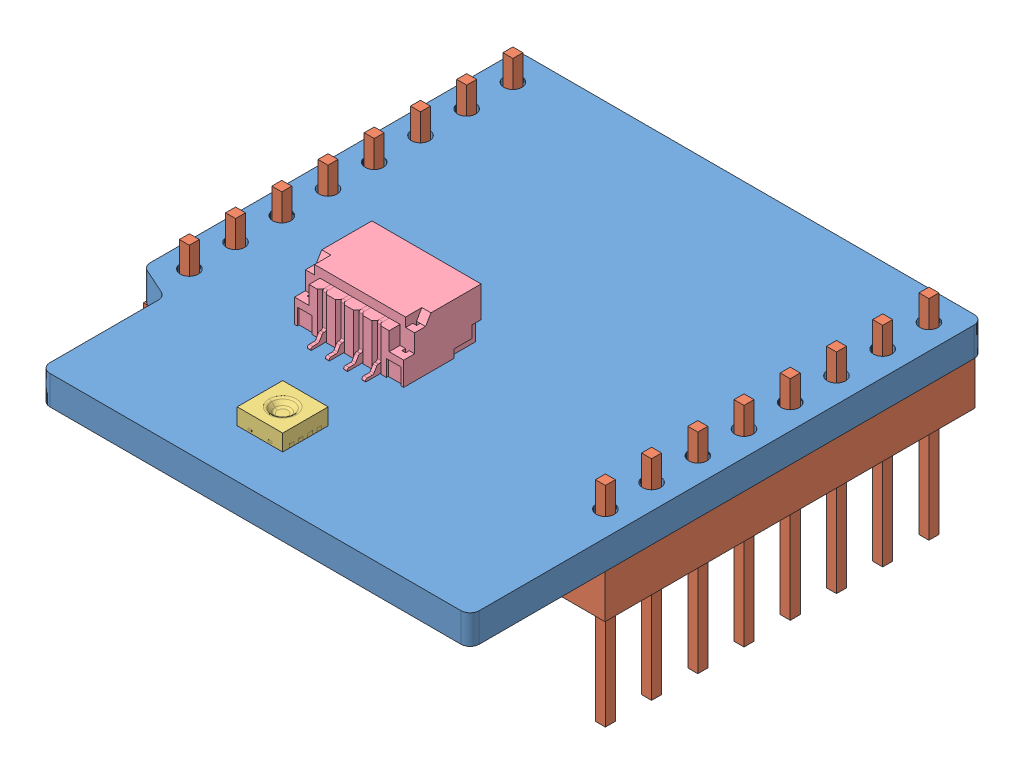
SolidWorks assembly LOLIN SHT30 shield v2.1.0, configuration Default. Lengths in mm.
Overall size (25.6 13 28.2).
5 component instances, 4 part files, 11 mates.
Components (placement in the parent):
- LOLIN template-1: LOLIN template [Default] at origin size (25.6 1.6 28.2)
- header_m8-1: header_m8 [Default] at (-11.43 -2.5 -27.85) x (0 0 1) z (-1 0 0) size (20.32 11.5 2.5)
- header_m8-2: header_m8 [Default] at (11.43 -2.5 -27.85) x (0 0 1) z (-1 0 0) size (20.32 11.5 2.5)
- Sensirion_Humidity_SHT3x_STEP-file.step-1: Sensirion_Humidity_SHT3x_STEP-file.step [Default] at (-0.95 2.0515 -3.45) size (2.5 0.9 2.5)
- SM4B-SRSS-TB.step-1: SM4B-SRSS-TB.step [Default] at (-1.3 1.6 -8.95) x (-1 0 0) z (0 1 0) size (6 4.95 2.95)
Mates (geometry in assembly coordinates):
- Coincident2: coincident anti-aligned: plane of breakout_template-1 through (0 0 0) normal (0 -1 0); plane of header_m8-1 through (-12.68 0 -27.85) normal (0 1 0)
- Coincident3: coincident anti-aligned: plane of breakout_template-1 through (0 0 0) normal (0 -1 0); plane of header_m8-2 through (10.18 0 -27.85) normal (0 1 0)
- Parallel1: parallel anti-aligned: plane of header_m8-1 through (-11.43 -2.5 -27.85) normal (-1 0 0)
- Parallel2: parallel anti-aligned: plane of header_m8-2 through (11.43 -2.5 -27.85) normal (-1 0 0)
- Coincident5: coincident aligned: line of breakout_template-1 through (-11.43 1.6 -26.58) axis (0 -1 0); line of header_m8-1 through (-11.43 -2.5 -26.58) axis (0 -1 0)
- Coincident6: coincident aligned: line of breakout_template-1 through (11.43 1.6 -26.58) axis (0 -1 0); line of header_m8-2 through (11.43 -2.5 -26.58) axis (0 -1 0)
- Distance1: distance = 2.2 mm aligned: plane of Sensirion_Humidity_SHT3x_STEP-file.step-1 through (-2.2 2.9515 -2.2) normal (0 0 1); plane of LOLIN template-1 through (-10.8 1.6 0) normal (0 0 1)
- Distance2: distance = 12.5 mm aligned: plane of Sensirion_Humidity_SHT3x_STEP-file.step-1 through (0.3 2.9515 -4.7) normal (1 0 0); plane of LOLIN template-1 through (12.8 1.6 0) normal (1 0 0)
- Coincident9: coincident anti-aligned: plane of LOLIN template-1 through (0 1.6 0) normal (0 1 0); plane of SM4B-SRSS-TB.step-1 through (-1.3 1.6 -8.95) normal (0 -1 0)
- Distance4: distance = 7 mm aligned: plane of SM4B-SRSS-TB.step-1 through (-5.8 1.6 -8.95) normal (-1 0 0); plane of LOLIN template-1 through (-12.8 1.6 -7.6905) normal (-1 0 0)
- Distance5: distance = 15 mm aligned: plane of SM4B-SRSS-TB.step-1 through (-1.3 1.6 -13.2) normal (0 0 -1); plane of LOLIN template-1 through (-12.8 1.6 -28.2) normal (0 0 -1)
